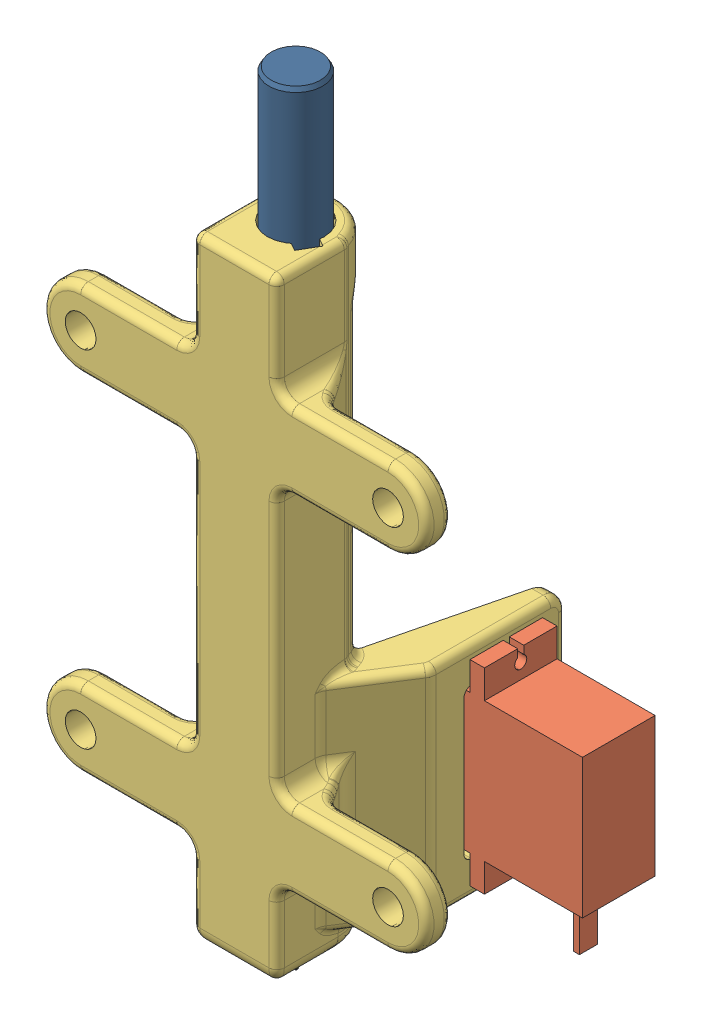
SolidWorks assembly PenHolder, configuration Default. Lengths in mm.
Overall size (64.55 129.45 48.11).
12 component instances, 11 part files, 16 mates.
Components (placement in the parent):
- Servo Lever-1: Servo Lever [Default] at (-0.5 -33.948 -30.734) x (0 -0.984808 -0.173648) z (0 -0.173648 0.984808) size (7.3 5 34)
- SG90 Servo-1: SG90 Servo [Default] at (9.8 -28.448 -30.734) x (0 1 0) z (0 0 1) size (37.7 30.3 12)
- PenHolder-1: PenHolder [Default] at origin size (63.5 101.91 40.64)
- Assembly Ink Cartridge Pilot G2-1: Assembly Ink Cartridge Pilot G2 [Default] at (-23.3837 82.6746 -54.1169) x (1 0 0) z (0 -1 0) size (8.33 8.33 120.93)
  - Ink Container Tube-2: Ink Container Tube [Default] at (23.3837 43.9569 29.8776) x (-1 0 0) z (0 1 0) size (6.2 88 6)
  - Ink Container Back Plug-1: Ink Container Back Plug [Default] at (23.3837 43.9569 29.8776) x (1 0 0) z (0 1 0) size (6 4.9 6)
  - Pen Tip Holder-1: Pen Tip Holder [Default] at (23.3837 43.9569 117.8776) x (0.558829 -0.829283 0) z (0.829283 0.558829 0) size (6 18.11 6)
  - Pen Tip-1: Pen Tip [Default] at (23.3837 43.9569 135.6644) x (0.943336 0.33184 0) z (-0.33184 0.943336 0) size (2.59 15.69 2.63)
  - Roller Ball-2: Roller Ball [Default] at (23.3837 43.9569 138.8644) x (0.307657 -0.299861 -0.903012) z (0.951494 0.099481 0.29114) size (0.5 0.5 0.5)
  - Spring-3: Spring [Write] at (23.3837 43.9569 20.2276) x (1 0 0) z (0 -1 0) size (7.26 11.16 7.26)
- Spring Cap-1: Spring Cap [Default] at (0 19.5395 -10.16) x (0.422618 0 0.906308) z (-0.906308 0 0.422618) size (8.89 53.34 10.92)
- Pen Lifter-1: Pen Lifter [Default] at (0 -47.625 -10.16) x (-1 0 0) z (0 0 -1) size (8.89 15.4 11.43)
Mates (geometry in assembly coordinates):
- Concentric1: concentric anti-aligned: cylinder of Servo Lever-1 through (4.5 -33.948 -30.734) axis (-1 0 0) radius 0.75; cylinder of SG90 Servo-1 through (5.5 -33.948 -30.734) axis (1 0 0) radius 6
- Coincident2: coordinate: point of PenHolder-1
- Concentric4: concentric anti-aligned: cylinder of PenHolder-1 through (0 -47.625 -10.16) axis (0 -1 0) radius 1.397; cylinder of Assembly Ink Cartridge Pilot G2-1/Ink Container Tube-2 through (0 -35.203 -10.16) axis (0 1 0) radius 3
- Coincident7: coincident anti-aligned: plane of Servo Lever-1 through (2.5 -33.948 -30.734) normal (1 0 0); plane of SG90 Servo-1 through (2.5 -28.448 -30.734) normal (-1 0 0)
- Parallel2: parallel aligned: plane of Assembly Ink Cartridge Pilot G2-1 through (-23.3837 82.6746 -54.1169) normal (0 0 1)
- Concentric5: concentric anti-aligned: cylinder of PenHolder-1 through (0 50.8 -10.16) axis (0 -1 0) radius 6.985; cylinder of Spring Cap-1 through (0 70.3395 -10.16) axis (0 1 0) radius 4.445
- Angle1: planar angle = 2.007129 rad anti-aligned: plane of Spring Cap-1 through (0 19.5395 -10.16) normal (-0.906308 0 0.422618)
- Concentric7: concentric anti-aligned: cylinder of PenHolder-1 through (0 50.8 -10.16) axis (0 -1 0) radius 4.699; cylinder of Pen Lifter-1 through (0 -36.703 -10.16) axis (0 1 0) radius 4.445
- Parallel5: parallel anti-aligned: plane of Pen Lifter-1 through (0 -47.625 -10.16) normal (0 0 -1)
- Symmetric2: symmetric aligned: plane of Servo Lever-1 through (-0.5 -31.3867 -45.2599) normal (-1 0 0); plane of Pen Lifter-1 through (0.5 -31.3867 -45.2599) normal (1 0 0); plane of Servo Lever-1 through (0 -47.625 -10.16) normal (-1 0 0)
- LimitAngle1: limit planar angle = 0.174533 rad aligned: plane of Servo Lever-1 through (-0.5 -33.948 -30.734) normal (0 -0.173648 0.984808); plane of SG90 Servo-1 through (9.8 -28.448 -30.734) normal (0 0 1)
- LimitDistance1: limit distance = 0 mm anti-aligned: plane of PenHolder-1 through (0 -47.625 -10.16) normal (0 1 0); plane of Pen Lifter-1 through (-4.445 -47.625 -10.16) normal (0 -1 0)
- Coincident14: coincident anti-aligned: plane of Assembly Ink Cartridge Pilot G2-1/Pen Tip Holder-1 through (0 -36.703 -10.16) normal (0 -1 0); plane of Pen Lifter-1 through (-2.3546 -36.703 -10.16) normal (0 1 0)
- Parallel6: parallel anti-aligned: plane of SG90 Servo-1 through (14.2 -28.448 -30.734) normal (-1 0 0); plane of PenHolder-1 through (14.2011 0 0) normal (1 0 0)
- Concentric8: concentric anti-aligned: cylinder of SG90 Servo-1 through (16.6 -14.4196 -30.734) axis (-1 0 0) radius 1; cylinder of PenHolder-1 through (11.6611 -14.4196 -30.734) axis (1 0 0) radius 0.635
- Parallel7: parallel aligned: plane of SG90 Servo-1 through (32.8 -39.948 -36.734) normal (0 0 -1); plane of PenHolder-1 through (11.6611 -12.248 -40.64) normal (0 0 -1)
